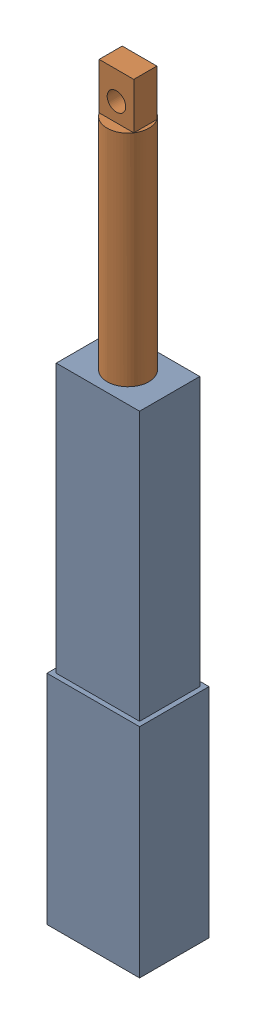
SolidWorks assembly actuator, configuration Default. Lengths in mm.
Overall size (20 162.43 15).
2 component instances, 2 part files, 2 mates.
Components (placement in the parent):
- actuator_base-1: actuator_base [Default] at (-1.2568 -34.19 38.8913) size (20 105 15)
- actuator_mover-1: actuator_mover [Default] at (8.7432 118.2403 31.3913) x (-1 0 0) z (0 0 1) size (9 60 9)
Mates (geometry in assembly coordinates):
- Concentric1: concentric anti-aligned: circle of actuator_base-1; circle of actuator_mover-1
- Parallel1: parallel aligned: plane of actuator_base-1 through (-0.2568 70.81 37.8913) normal (0 0 1); plane of actuator_mover-1 through (4.999 128.2403 33.8875) normal (0 0 1)
